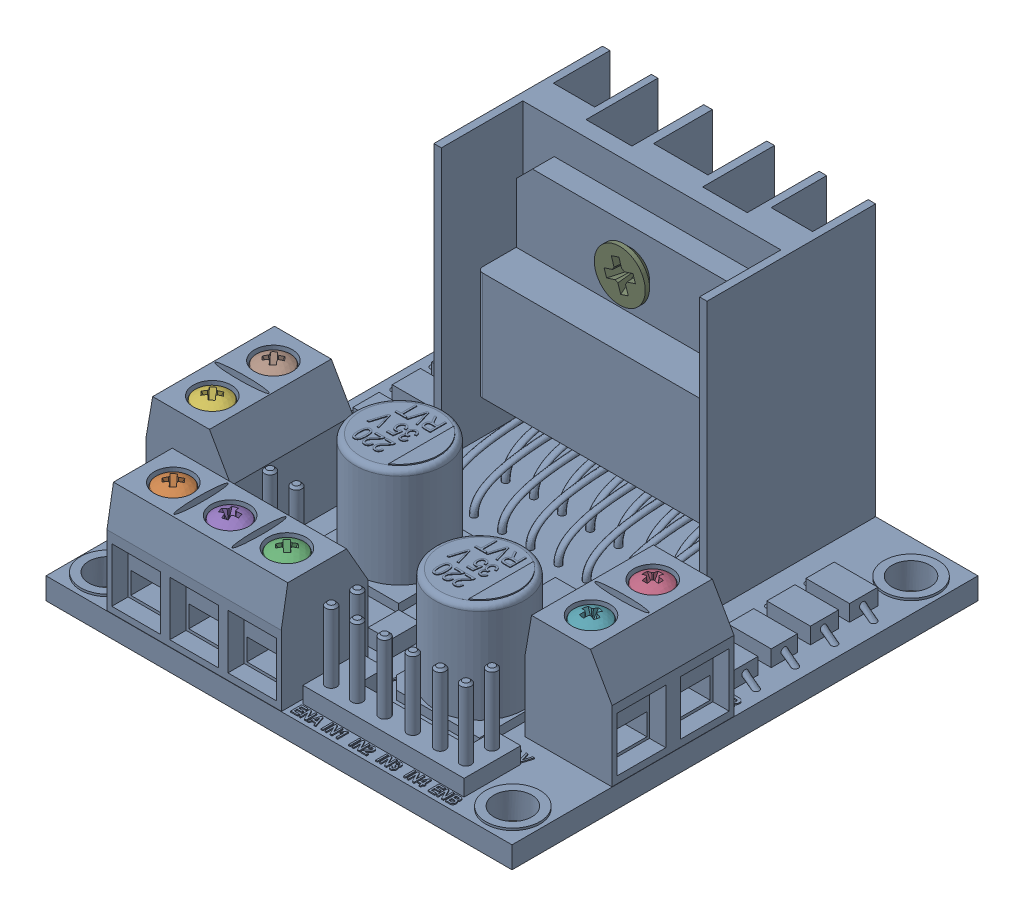
SolidWorks assembly L298N-1, configuration Varsayılan. Lengths in mm.
Overall size (43 28.01 43).
9 component instances, 3 part files, 0 mates.
Components (placement in the parent):
- L298N Stepper Motor Driver (Red)-Part File-1: L298N Stepper Motor Driver (Red)-Part File [Varsayılan] at (16.8606 10.1012 32.1341) size (43 28.01 43)
- pan head cross recess screw_iso_ISO 7045 - M1.6 x 4 - Z - 4N-1: pan head cross recess screw_iso_ISO 7045 - M1.6 x 4 - Z - 4N [Varsayılan] at (3.7852 22.4012 50.3107) x (0 -1 0) z (0.734198 0 -0.678936) size (5.3 3.2 3.23)
- pan head cross recess screw_iso_ISO 7045 - M1.6 x 4 - Z - 4N-2: pan head cross recess screw_iso_ISO 7045 - M1.6 x 4 - Z - 4N [Varsayılan] at (14.2688 22.4012 50.3107) x (0 -1 0) z (0.720108 0 0.693862) size (5.3 3.2 3.23)
- pan head cross recess screw_iso_ISO 7045 - M1.6 x 4 - Z - 4N-3: pan head cross recess screw_iso_ISO 7045 - M1.6 x 4 - Z - 4N [Varsayılan] at (33.6606 22.4012 35.9476) x (0 -1 0) z (0 0 1) size (5.3 3.2 3.23)
- pan head cross recess screw_iso_ISO 7045 - M1.6 x 4 - Z - 4N-4: pan head cross recess screw_iso_ISO 7045 - M1.6 x 4 - Z - 4N [Varsayılan] at (9.027 22.4012 50.3107) x (0 -1 0) z (0.308372 0 0.951266) size (5.3 3.2 3.23)
- pan head cross recess screw_iso_ISO 7045 - M1.6 x 4 - Z - 4N-5: pan head cross recess screw_iso_ISO 7045 - M1.6 x 4 - Z - 4N [Varsayılan] at (-1.3394 22.4012 41.5921) x (0 -1 0) z (-0.751552 0 0.659674) size (5.3 3.2 3.23)
- pan head cross recess screw_iso_ISO 7045 - M1.6 x 4 - Z - 4N-6: pan head cross recess screw_iso_ISO 7045 - M1.6 x 4 - Z - 4N [Varsayılan] at (33.6606 22.4012 41.6421) x (0 -1 0) z (-0.222944 0 0.974831) size (5.3 3.2 3.23)
- pan head cross recess screw_iso_ISO 7045 - M1.6 x 4 - Z - 4N-7: pan head cross recess screw_iso_ISO 7045 - M1.6 x 4 - Z - 4N [Varsayılan] at (-1.3394 22.4012 35.9476) x (0 -1 0) z (-0.742963 0 0.669332) size (5.3 3.2 3.23)
- countersunk flat head cross recess screw_iso_ISO 7046-1 - M2.5 x 3 - Z - 3N-1: countersunk flat head cross recess screw_iso_ISO 7046-1 - M2.5 x 3 - Z - 3N [Varsayılan] at (16.3567 30.6012 21.6857) x (0 0 -1) z (-0.309066 0.951041 0) size (3 4.7 4.7)
